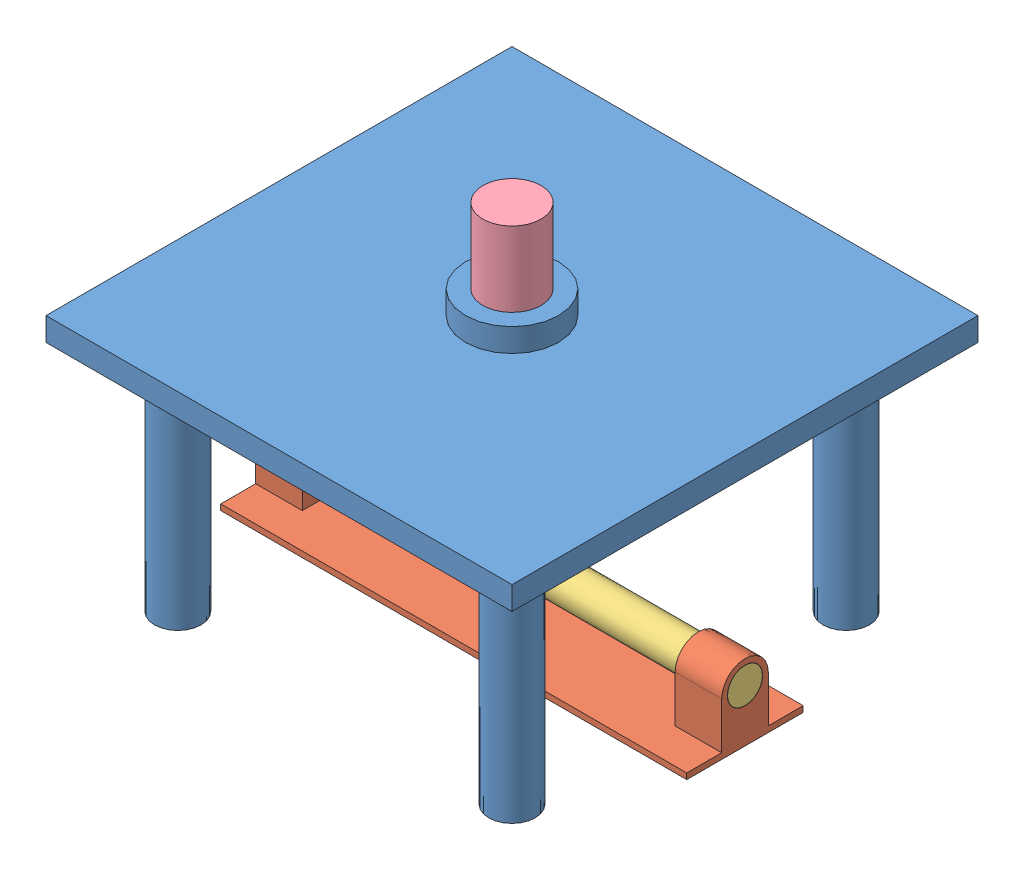
SolidWorks assembly CAM Follower, configuration Default. Lengths in mm.
Overall size (400 304.18 400).
4 component instances, 4 part files, 9 mates.
Components (placement in the parent):
- stoolsupp-1: stoolsupp [Default] at (-303.6748 -160.8941 400.3804) size (400 240 400)
- basebearings-1: basebearings [Default] at (-303.6748 -160.8941 400.3804) size (400 65 100)
- CAM-1: CAM [Default] at (-303.6748 -115.8941 400.3804) x (0 -0.299504 0.954095) z (1 0 0) size (53.6 55.19 400)
- follower-1: follower [Default] at (-303.6748 -56.7145 400.3804) size (50 230 60)
Mates (geometry in assembly coordinates):
- Parallel1: parallel aligned: plane of stoolsupp-1 through (-160.2434 -160.8941 543.8118) normal (0 -1 0); plane of basebearings-1 through (-303.6748 -160.8941 400.3804) normal (0 -1 0)
- Coincident2: coincident aligned: plane of stoolsupp-1 through (-103.6748 59.1059 200.3804) normal (1 0 0); plane of basebearings-1 through (-103.6748 -155.8941 350.3804) normal (1 0 0)
- Concentric1: concentric anti-aligned: circle of stoolsupp-1; cylinder of basebearings-1 through (-303.6748 -155.3941 400.3804) axis (0 -1 0) radius 0.3202
- Coincident4: coincident aligned: plane of stoolsupp-1 through (-447.1063 -160.8941 256.9489) normal (0 -1 0); plane of basebearings-1 through (-303.6748 -160.8941 400.3804) normal (0 -1 0)
- Concentric2: concentric anti-aligned: cylinder of basebearings-1 through (-143.6748 -115.8941 400.3804) axis (1 0 0) radius 15.1805; cylinder of CAM-1 through (-103.6748 -115.8941 400.3804) axis (-1 0 0) radius 15
- Coincident5: coincident aligned: plane of basebearings-1 through (-503.6748 -155.8941 350.3804) normal (-1 0 0); plane of CAM-1 through (-503.6748 -115.8941 400.3804) normal (-1 0 0)
- Concentric3: concentric anti-aligned: circle of stoolsupp-1; cylinder of follower-1 through (-303.6748 143.2855 400.3804) axis (0 -1 0) radius 25
- Parallel2: parallel anti-aligned: cylinder of CAM-1 through (-503.6748 -115.8941 400.3804) axis (1 0 0) radius 15; cylinder of follower-1 through (-288.6748 -56.7145 400.3804) axis (-1 0 0) radius 30
- Tangent3: tangent: face of CAM-1; cylinder of follower-1 through (-288.6748 -56.7145 400.3804) axis (-1 0 0) radius 30
